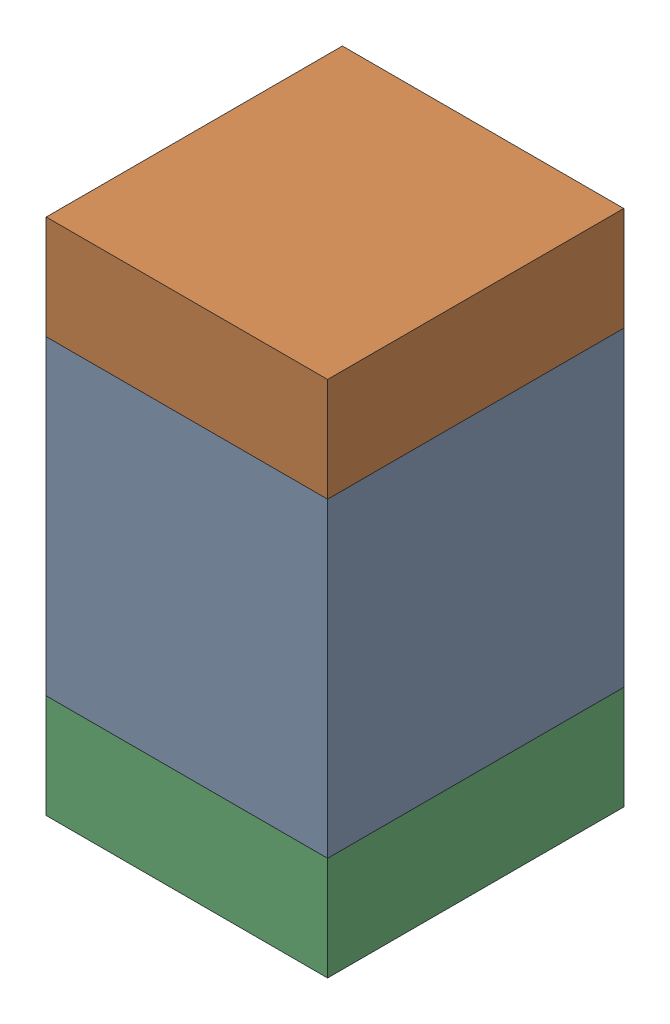
SolidWorks assembly C309_1PCB, configuration Default. Lengths in mm.
Overall size (0.95 1.75 1).
6 component instances, 2 part files, 0 mates.
Components (placement in the parent):
- 761616384-1: 761616384 [Default] at (125.6343 113.35 0) size (0.95 1.05 1)
  - Extruded_5-1: Extruded_5 [Default] at origin size (0.95 1.05 1)
- 761616520-1: 761616520 [Default] at (125.6343 114.05 0) size (0.95 0.35 1)
  - Extruded_6-1: Extruded_6 [Default] at origin size (0.95 0.35 1)
- 761616520-2: 761616520 [Default] at (125.6343 112.65 0) size (0.95 0.35 1)
  - Extruded_6-1: Extruded_6 [Default] at origin size (0.95 0.35 1)
